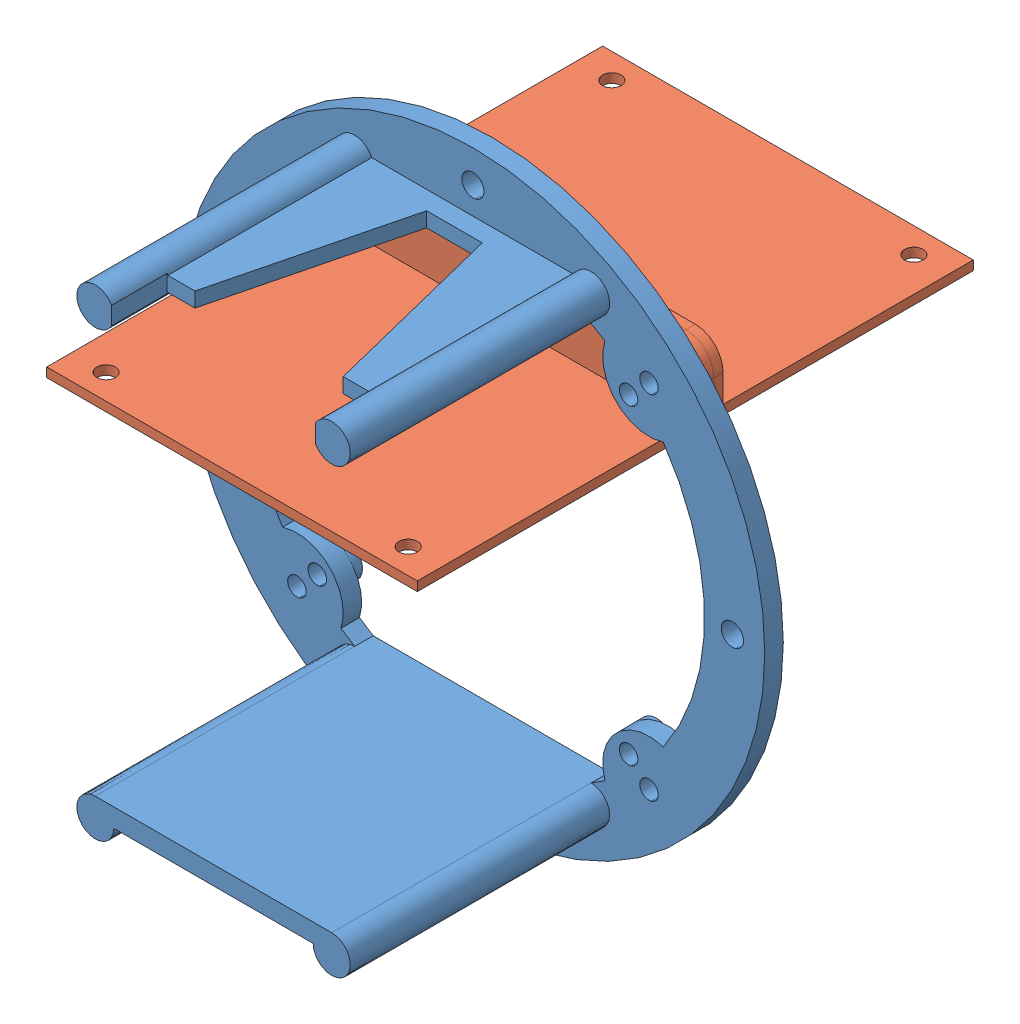
SolidWorks assembly Assem1, configuration Default. Lengths in mm.
Overall size (63 63 73.45).
3 component instances, 2 part files, 6 mates.
Components (placement in the parent):
- inner_plastic_brk-1: inner_plastic_brk [Default] at origin size (63 63 31)
- MD_bracket-1: MD_bracket [Default] at (0 13 -2) x (0 0 -1) z (1 0 0) size (36.72 9 44)
- MD_bracket-2: MD_bracket [Default] at (0 13 -2) x (0 0 1) z (-1 0 0) size (36.72 9 44)
Mates (geometry in assembly coordinates):
- Concentric1: concentric aligned: cylinder of inner_plastic_brk-1 through (19 19 2) axis (0 0 -1) radius 1; circle of MD_bracket-1
- Concentric2: concentric anti-aligned: circle of inner_plastic_brk-1; circle of MD_bracket-1
- Coincident1: coincident anti-aligned: plane of inner_plastic_brk-1 through (19 -19 -1) normal (0 0 -1); plane of MD_bracket-1 through (-22 22 -1) normal (0 0 1)
- Coincident2: coincident anti-aligned: plane of MD_bracket-1 through (20 14 -1) normal (0 0 -1); plane of MD_bracket-2 through (-20 14 -1) normal (0 0 1)
- Concentric3: concentric anti-aligned: circle of MD_bracket-1; circle of MD_bracket-2
- Coincident4: coincident anti-aligned: cylinder of MD_bracket-1 through (19 19 0) axis (0 0 -1) radius 1.1; circle of MD_bracket-2
